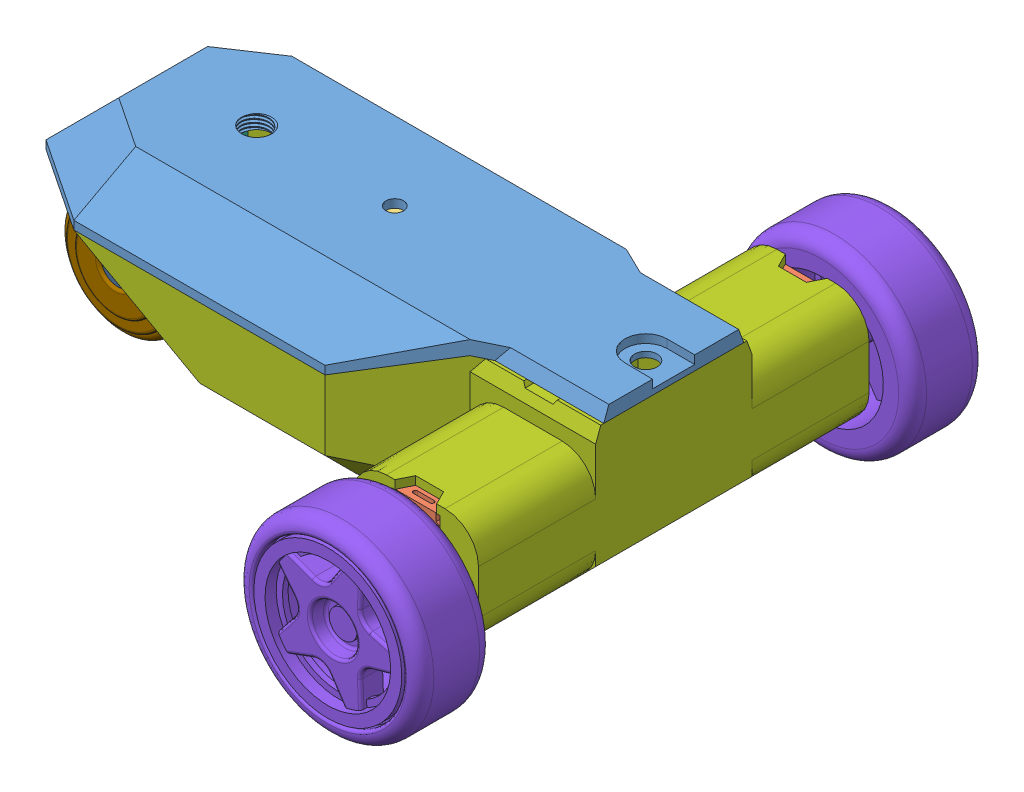
SolidWorks assembly 어셈블리1, configuration 기본. Lengths in mm.
Overall size (245.75 77.73 203).
13 component instances, 10 part files, 25 mates.
Components (placement in the parent):
- 상단-1: 상단 [기본] at origin size (211.23 20.44 115.75)
- 바퀴모터-1: 바퀴모터 [기본] at (77.5 -15 69.9) x (1 0 0) z (0 1 0) size (42 28.6 37.85)
- 아두이노-1: 아두이노 [기본] at (-4.6951 -5.181 5.9258) size (77 20 54)
- 건전지-1: 건전지 [기본] at (-1.8966 -34.9128 0.4596) size (70 32 40)
- 모터드라이버-1: 모터드라이버 [기본] at (63.0434 -22.5957 1.9577) x (0.991175 0 -0.13256) z (0.13256 0 0.991175) size (35 11.6 32)
- 서보(조향)-1: 서보(조향) [기본] at (-69.75 12.701 0.3) x (0 0 -1) z (-1 0 0) size (12 34.5 32.5)
- 하단-1: 하단 [기본] at (0 -40 0) size (200 55 140)
- 뒷바퀴-1: 뒷바퀴 [기본] at (77.5 -23.1 75.1) x (0 -1 0) z (0 0 1) size (66 66 30)
- 앞바꾸2-1: 앞바꾸2 [기본] at (-85.95 -35.4899 9.3) x (1 0 0) z (0 1 0) size (43.6 10 43.6)
- 뒷바퀴-2: 뒷바퀴 [기본] at (77.5 -23.1 -75.1) x (0 1 0) z (0 0 -1) size (66 66 30)
- 모터드라이버-2: 모터드라이버 [기본] at (56.9651 -33.6959 2.7706) x (0.991175 0 -0.13256) z (0.13256 0 0.991175) size (35 11.6 32)
- 바퀴모터-2: 바퀴모터 [기본] at (77.5 -15 -69.9) x (-1 0 0) z (0 1 0) size (42 28.6 37.85)
- 조향-1: 조향 [기본] at (-85.95 -35.4899 -6.7) size (35.7 28.5 20)
Mates (geometry in assembly coordinates):
- 일치12: coincident: plane of 바퀴모터-1 through (71.3646 -24.6 73.5) normal (0 -1 0); plane of 뒷바퀴-1 through (75.5 -24.6 77.5) normal (0 1 0)
- 일치13: coincident: plane of 바퀴모터-1 through (77.5 -23.1 71.5) normal (0 0 1); plane of 뒷바퀴-1 through (77.5 -23.1 71.5) normal (0 0 -1)
- 동심1: concentric: cylinder of 바퀴모터-1 through (77.5 -23.1 79.5) axis (0 0 -1) radius 2.5; circle of 뒷바퀴-1
- 평행2: parallel: plane of 하단-1 through (-70 15 45) normal (0 0 1); plane of 앞바꾸2-1 through (-32.3935 -98.5144 5.3) normal (0 0 -1)
- 동심2: concentric: cylinder of 바퀴모터-1 through (77.5 -15 50.9) axis (0 0 1) radius 14; cylinder of 하단-1 through (77.5 -15 50.9) axis (0 0 1) radius 14.075
- 일치14: coincident: plane of 상단-1 through (55 15 -61) normal (0 -1 0); plane of 하단-1 through (0 15 0) normal (0 1 0)
- 일치15: coincident: plane of 상단-1 through (100 20 28) normal (1 0 0); plane of 하단-1 through (100 15 28) normal (1 0 0)
- 일치16: coincident: plane of 상단-1 through (-70 20 45) normal (0 0 1); plane of 하단-1 through (-70 15 45) normal (0 0 1)
- 평행3: parallel: plane of 하단-1 through (0 -40 -70) normal (0 0 -1); plane of 바퀴모터-2 through (77.5 -15 -50.9) normal (0 0 1)
- 평행4: parallel: plane of 하단-1 through (55 5 70) normal (0 1 0); plane of 바퀴모터-2 through (84.75 2 -53.4) normal (0 1 0)
- 일치20: coincident: plane of 뒷바퀴-2 through (77.5 -23.1 -71.5) normal (0 0 1); plane of 바퀴모터-2 through (77.5 -23.1 -71.5) normal (0 0 -1)
- 동심8: concentric: cylinder of 뒷바퀴-2 through (77.5 -23.1 -71.5) axis (0 0 -1) radius 4.9; cylinder of 바퀴모터-2 through (77.5 -23.1 -71.5) axis (0 0 1) radius 4.6
- 평행8: parallel: plane of 상단-1 through (0 20 0) normal (0 1 0); plane of 모터드라이버-1 through (63.0434 -10.9957 1.9577) normal (0 1 0)
- 일치22: coincident: plane of 모터드라이버-1 through (48.4598 -10.9957 -9.0179) normal (-0.13256 0 -0.991175); plane of 모터드라이버-2 through (42.3814 -22.0959 -8.205) normal (-0.13256 0 -0.991175)
- 평행9: parallel: plane of 바퀴모터-1 through (70.25 2 53.4) normal (0 1 0); plane of 하단-1 through (68.75 1.925 50.9) normal (0 -1 0)
- 일치24: coincident: plane of 바퀴모터-1 through (77.5 -15 50.9) normal (0 0 -1); plane of 하단-1 through (77.5 -15 50.9) normal (0 0 1)
- 일치25: coincident: plane of 서보(조향)-1 through (-69.75 -9.999 0.3) normal (0 -1 0); plane of 하단-1 through (0 -9.999 0) normal (0 1 0)
- 일치26: coincident: plane of 하단-1 through (-53.5 -9.999 6.4) normal (-1 0 0); plane of 서보(조향)-1 through (-53.5 -5.899 6.3) normal (1 0 0)
- 거리1: distance = 0.1 mm: plane of 서보(조향)-1 through (-81.25 -9.999 6.3) normal (0 0 1); plane of 하단-1 through (-86.5 -9.999 6.4) normal (0 0 -1)
- 일치27: coincident: plane of 앞바꾸2-1 through (-32.3935 -98.5144 13.3) normal (0 0 1); plane of 조향-1 through (-85.95 -35.4899 13.3) normal (0 0 1)
- 일치28: coincident: plane of 서보(조향)-1 through (-64.25 -21.799 0.3) normal (0 -1 0); plane of 조향-1 through (-65.25 -21.799 2.8) normal (0 1 0)
- 동심10: concentric: cylinder of 서보(조향)-1 through (-64.25 -17.799 0.3) axis (0 -1 0) radius 3.5; cylinder of 조향-1 through (-64.25 -35.4899 0.3) axis (0 -1 0) radius 5
- 동심11: concentric: cylinder of 하단-1 through (77.5 -15 -50.9) axis (0 0 -1) radius 14.075; cylinder of 바퀴모터-2 through (77.5 -15 -50.9) axis (0 0 -1) radius 14
- 일치29: coincident: plane of 하단-1 through (77.5 -15 -50.9) normal (0 0 -1); plane of 바퀴모터-2 through (77.5 -15 -50.9) normal (0 0 1)
- 동심12: concentric: cylinder of 앞바꾸2-1 through (-85.95 -35.4899 4.3) axis (0 0 1) radius 6; cylinder of 조향-1 through (-85.95 -35.4899 13.3) axis (0 0 -1) radius 6
